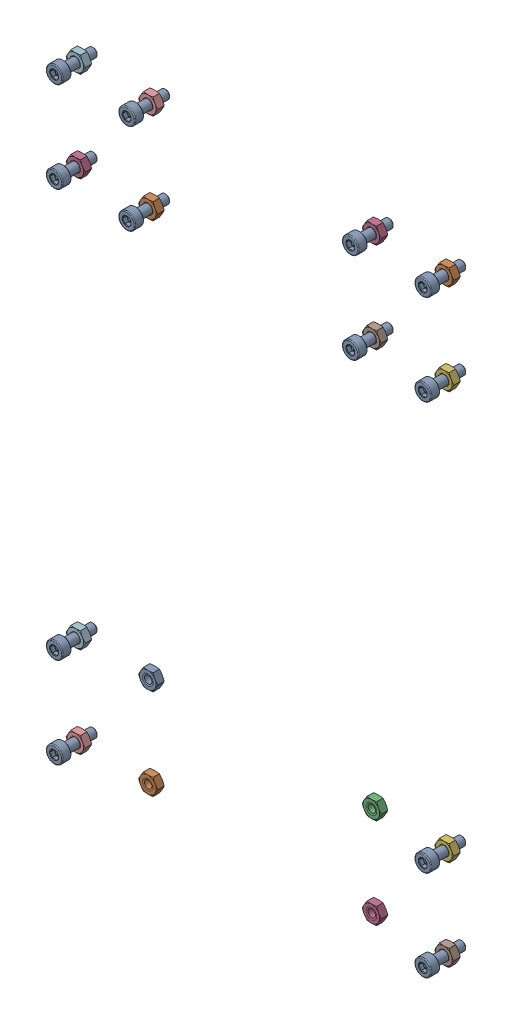
SolidWorks assembly Fasteners005, configuration Varsayılan. Lengths in mm.
Overall size (128.35 200.5 13.14).
40 component instances, 28 part files, 0 mates.
Components (placement in the parent):
- Screw and Nut M3x010_011-1: Screw and Nut M3x010_011 [Varsayılan] at (61 64.5 0) size (6.35 5.5 13.14)
  - M3x10-Screw010-1: M3x10-Screw010 [Varsayılan] at origin size (5.5 5.5 13.14)
  - M3-Nut042-1: M3-Nut042 [Varsayılan] at (0 0 -4) x (-1 0 0) z (0 0 -1) size (6.35 5.5 2.4)
- Screw and Nut M3x010_022-1: Screw and Nut M3x010_022 [Varsayılan] at (37 64.5 0) size (6.35 5.5 13.14)
  - M3x10-Screw021-1: M3x10-Screw021 [Varsayılan] at origin size (5.5 5.5 13.14)
  - M3-Nut053-1: M3-Nut053 [Varsayılan] at (0 0 -4) x (-1 0 0) z (0 0 -1) size (6.35 5.5 2.4)
- Screw and Nut M3x010_021-1: Screw and Nut M3x010_021 [Varsayılan] at (61 34.5 0) size (6.35 5.5 13.14)
  - M3x10-Screw020-1: M3x10-Screw020 [Varsayılan] at origin size (5.5 5.5 13.14)
  - M3-Nut052-1: M3-Nut052 [Varsayılan] at (0 0 -4) x (-1 0 0) z (0 0 -1) size (6.35 5.5 2.4)
- Screw and Nut M3x010_020-1: Screw and Nut M3x010_020 [Varsayılan] at (37 34.5 0) size (6.35 5.5 13.14)
  - M3x10-Screw019-1: M3x10-Screw019 [Varsayılan] at origin size (5.5 5.5 13.14)
  - M3-Nut051-1: M3-Nut051 [Varsayılan] at (0 0 -4) x (-1 0 0) z (0 0 -1) size (6.35 5.5 2.4)
- Screw and Nut M3x010_019-1: Screw and Nut M3x010_019 [Varsayılan] at (-37 64.5 0) size (6.35 5.5 13.14)
  - M3x10-Screw018-1: M3x10-Screw018 [Varsayılan] at origin size (5.5 5.5 13.14)
  - M3-Nut050-1: M3-Nut050 [Varsayılan] at (0 0 -4) x (-1 0 0) z (0 0 -1) size (6.35 5.5 2.4)
- Screw and Nut M3x010_018-1: Screw and Nut M3x010_018 [Varsayılan] at (-61 64.5 0) size (6.35 5.5 13.14)
  - M3x10-Screw017-1: M3x10-Screw017 [Varsayılan] at origin size (5.5 5.5 13.14)
  - M3-Nut049-1: M3-Nut049 [Varsayılan] at (0 0 -4) x (-1 0 0) z (0 0 -1) size (6.35 5.5 2.4)
- Screw and Nut M3x010_017-1: Screw and Nut M3x010_017 [Varsayılan] at (-37 34.5 0) size (6.35 5.5 13.14)
  - M3x10-Screw016-1: M3x10-Screw016 [Varsayılan] at origin size (5.5 5.5 13.14)
  - M3-Nut048-1: M3-Nut048 [Varsayılan] at (0 0 -4) x (-1 0 0) z (0 0 -1) size (6.35 5.5 2.4)
- Screw and Nut M3x010_016-1: Screw and Nut M3x010_016 [Varsayılan] at (-61 34.5 0) size (6.35 5.5 13.14)
  - M3x10-Screw015-1: M3x10-Screw015 [Varsayılan] at origin size (5.5 5.5 13.14)
  - M3-Nut047-1: M3-Nut047 [Varsayılan] at (0 0 -4) x (-1 0 0) z (0 0 -1) size (6.35 5.5 2.4)
- Screw and Nut M3x010_015-1: Screw and Nut M3x010_015 [Varsayılan] at (61 -100.5 0) size (6.35 5.5 13.14)
  - M3x10-Screw014-1: M3x10-Screw014 [Varsayılan] at origin size (5.5 5.5 13.14)
  - M3-Nut046-1: M3-Nut046 [Varsayılan] at (0 0 -4) x (-1 0 0) z (0 0 -1) size (6.35 5.5 2.4)
- Screw and Nut M3x010_014-1: Screw and Nut M3x010_014 [Varsayılan] at (61 -130.5 0) size (6.35 5.5 13.14)
  - M3x10-Screw013-1: M3x10-Screw013 [Varsayılan] at origin size (5.5 5.5 13.14)
  - M3-Nut045-1: M3-Nut045 [Varsayılan] at (0 0 -4) x (-1 0 0) z (0 0 -1) size (6.35 5.5 2.4)
- Screw and Nut M3x010_013-1: Screw and Nut M3x010_013 [Varsayılan] at (-61 -130.5 0) size (6.35 5.5 13.14)
  - M3x10-Screw012-1: M3x10-Screw012 [Varsayılan] at origin size (5.5 5.5 13.14)
  - M3-Nut044-1: M3-Nut044 [Varsayılan] at (0 0 -4) x (-1 0 0) z (0 0 -1) size (6.35 5.5 2.4)
- Screw and Nut M3x010_012-1: Screw and Nut M3x010_012 [Varsayılan] at (-61 -100.5 0) size (6.35 5.5 13.14)
  - M3x10-Screw011-1: M3x10-Screw011 [Varsayılan] at origin size (5.5 5.5 13.14)
  - M3-Nut043-1: M3-Nut043 [Varsayılan] at (0 0 -4) x (-1 0 0) z (0 0 -1) size (6.35 5.5 2.4)
- M3-Nut058-1: M3-Nut058 [Varsayılan] at (-37 -100.5 -4) x (-1 0 0) z (0 0 -1) size (6.35 5.5 2.4)
- M3-Nut059-1: M3-Nut059 [Varsayılan] at (-37 -130.5 -4) x (-1 0 0) z (0 0 -1) size (6.35 5.5 2.4)
- M3-Nut060-1: M3-Nut060 [Varsayılan] at (37 -100.5 -4) x (-1 0 0) z (0 0 -1) size (6.35 5.5 2.4)
- M3-Nut066-1: M3-Nut066 [Varsayılan] at (37 -130.5 -4) x (-1 0 0) z (0 0 -1) size (6.35 5.5 2.4)
